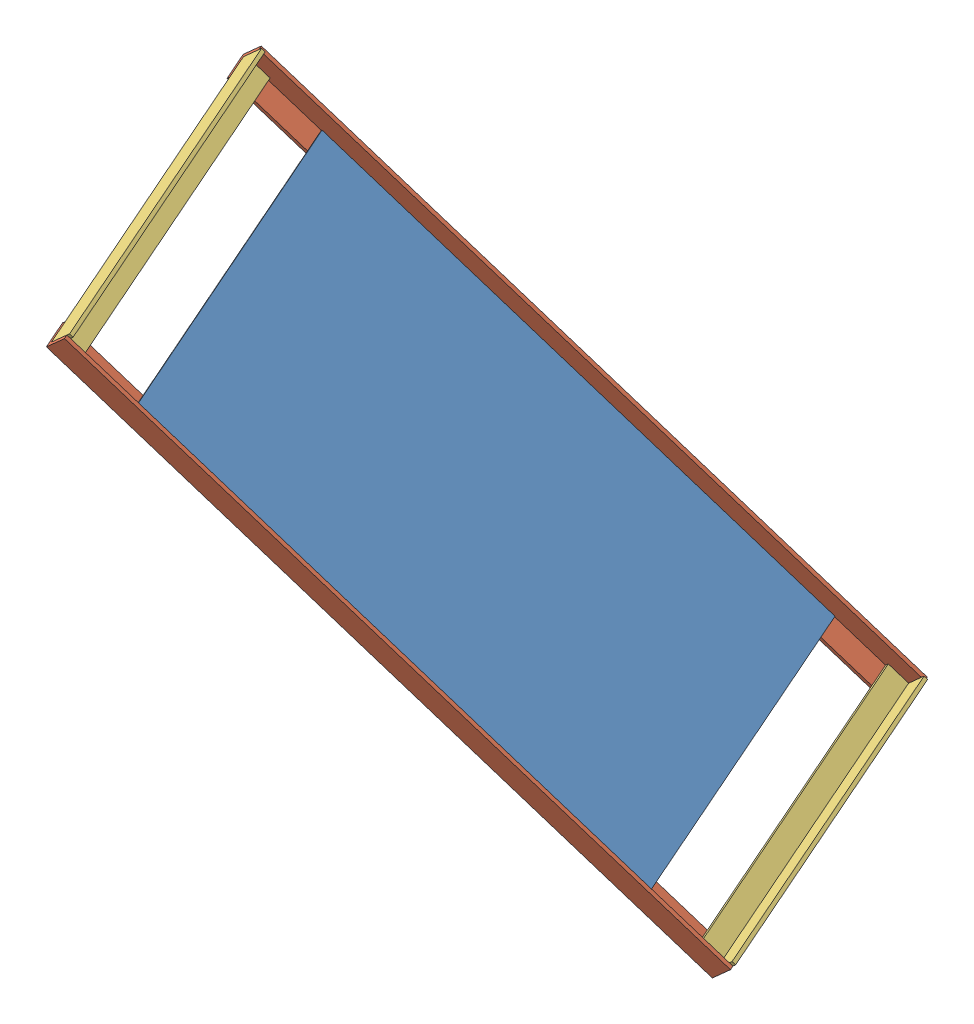
SolidWorks assembly Plate head, configuration Default. Lengths in mm.
Overall size (569.87 631.16 586.36).
5 component instances, 3 part files, 15 mates.
Components (placement in the parent):
- Holy Plate-1: Holy Plate [Default] at (-16.7971 305.3439 -129.0134) x (0.616571 -0.692474 -0.374592) z (0.25462 -0.274837 0.927164) size (580 1 310)
- Plate holder 75.3cm-1: Plate holder 75.3cm [Default] at (247.5932 3.9711 -137.8008) x (0.25462 -0.274837 0.927164) z (-0.616571 0.692474 0.374592) size (27 27 753)
- Plate holder 32cm-1: Plate holder 32cm [Default] at (158.3037 106.9627 -403.082) x (0.616571 -0.692474 -0.374592) z (0.25462 -0.274837 0.927164) size (27 27 320)
- Plate holder 32cm-2: Plate holder 32cm [Default] at (-191.2014 503.0542 155.4507) x (-0.616571 0.692474 0.374592) z (-0.25462 0.274837 -0.927164) size (27 27 320)
- Plate holder 75.3cm-2: Plate holder 75.3cm [Default] at (191.0674 104.7072 -417.0624) x (-0.744989 -0.667041 0.006861) z (-0.616571 0.692474 0.374592) size (27 27 753)
Mates (geometry in assembly coordinates):
- Coincident38: coincident: Holy Plate-1, Plate holder 75.3cm-1
- Coincident39: coincident: Holy Plate-1, Plate holder 75.3cm-2
- Distance7: distance: Holy Plate-1, Plate holder 32cm-1
- Coincident40: coincident: Plate holder 75.3cm-1, Plate holder 32cm-1
- Coincident42: coincident: Plate holder 75.3cm-1, Plate holder 32cm-1
- Coincident43: coincident: Plate holder 75.3cm-1, Plate holder 32cm-1
- Coincident44: coincident: Plate holder 32cm-1, Plate holder 75.3cm-2
- Coincident45: coincident: Plate holder 32cm-1, Plate holder 75.3cm-2
- Coincident46: coincident: Plate holder 32cm-1, Plate holder 75.3cm-2
- Coincident47: coincident: Plate holder 75.3cm-1, Plate holder 32cm-2
- Coincident48: coincident: Plate holder 75.3cm-1, Plate holder 32cm-2
- Coincident49: coincident: Plate holder 75.3cm-1, Plate holder 32cm-2
- Coincident50: coincident: Plate holder 32cm-2, Plate holder 75.3cm-2
- Coincident51: coincident: Plate holder 32cm-2, Plate holder 75.3cm-2
- Coincident52: coincident: Holy Plate-1, Plate holder 75.3cm-2
